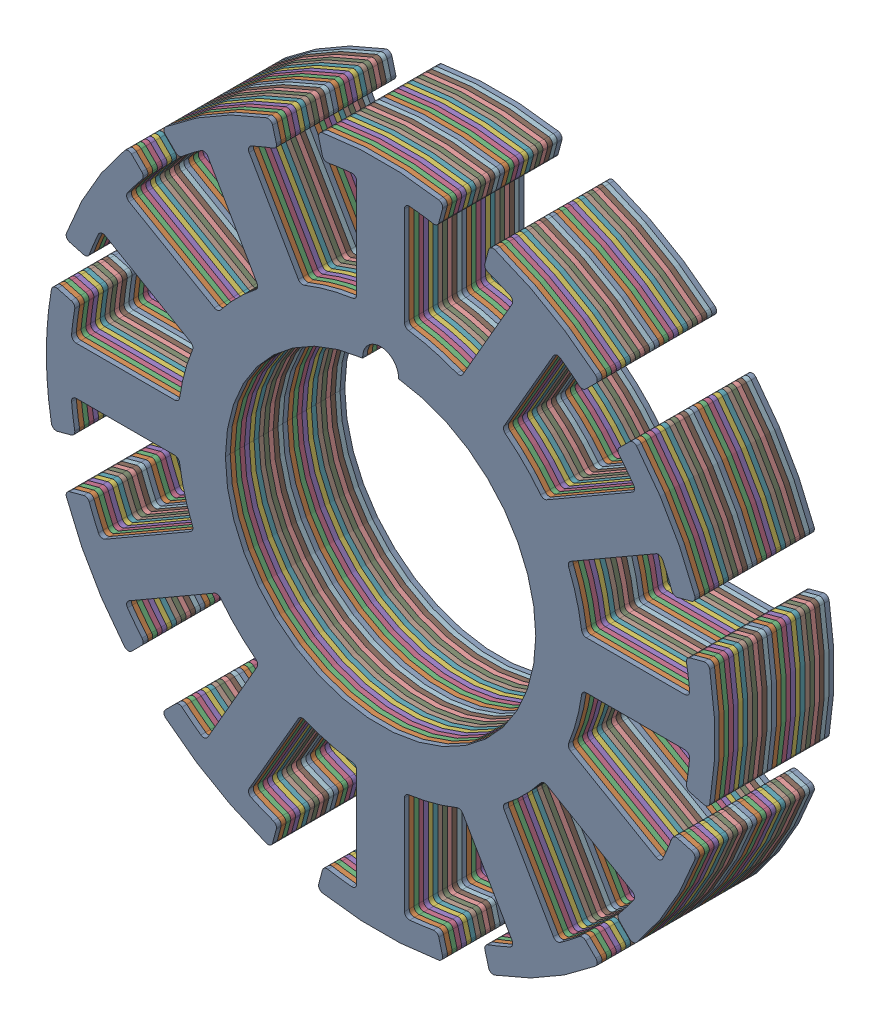
SolidWorks assembly 28x13x5mm-Stator.STEP, configuration Default. Lengths in mm.
Overall size (28 28 5).
30 component instances, 1 part files, 0 mates.
Components (placement in the parent):
- 28x13x1mm-Stator.STEP-1: 28x13x1mm-Stator.STEP [Default] at (34.0086 1.4103 18.4307) size (28 28 1)
  - 28x13-Stator Plate.STEP-1: 28x13-Stator Plate.STEP [Default] at (-28.2175 12.5042 6.2948) size (28 28 0.2)
  - 28x13-Stator Plate.STEP-2: 28x13-Stator Plate.STEP [Default] at (-28.2175 12.5042 6.0948) size (28 28 0.2)
  - 28x13-Stator Plate.STEP-3: 28x13-Stator Plate.STEP [Default] at (-28.2175 12.5042 5.8948) size (28 28 0.2)
  - 28x13-Stator Plate.STEP-4: 28x13-Stator Plate.STEP [Default] at (-28.2175 12.5042 5.6948) size (28 28 0.2)
  - 28x13-Stator Plate.STEP-5: 28x13-Stator Plate.STEP [Default] at (-28.2175 12.5042 5.4948) size (28 28 0.2)
- 28x13x1mm-Stator.STEP-2: 28x13x1mm-Stator.STEP [Default] at (34.0086 1.4103 17.4307) size (28 28 1)
  - 28x13-Stator Plate.STEP-1: 28x13-Stator Plate.STEP [Default] at (-28.2175 12.5042 6.2948) size (28 28 0.2)
  - 28x13-Stator Plate.STEP-2: 28x13-Stator Plate.STEP [Default] at (-28.2175 12.5042 6.0948) size (28 28 0.2)
  - 28x13-Stator Plate.STEP-3: 28x13-Stator Plate.STEP [Default] at (-28.2175 12.5042 5.8948) size (28 28 0.2)
  - 28x13-Stator Plate.STEP-4: 28x13-Stator Plate.STEP [Default] at (-28.2175 12.5042 5.6948) size (28 28 0.2)
  - 28x13-Stator Plate.STEP-5: 28x13-Stator Plate.STEP [Default] at (-28.2175 12.5042 5.4948) size (28 28 0.2)
- 28x13x1mm-Stator.STEP-3: 28x13x1mm-Stator.STEP [Default] at (34.0086 1.4103 16.4307) size (28 28 1)
  - 28x13-Stator Plate.STEP-1: 28x13-Stator Plate.STEP [Default] at (-28.2175 12.5042 6.2948) size (28 28 0.2)
  - 28x13-Stator Plate.STEP-2: 28x13-Stator Plate.STEP [Default] at (-28.2175 12.5042 6.0948) size (28 28 0.2)
  - 28x13-Stator Plate.STEP-3: 28x13-Stator Plate.STEP [Default] at (-28.2175 12.5042 5.8948) size (28 28 0.2)
  - 28x13-Stator Plate.STEP-4: 28x13-Stator Plate.STEP [Default] at (-28.2175 12.5042 5.6948) size (28 28 0.2)
  - 28x13-Stator Plate.STEP-5: 28x13-Stator Plate.STEP [Default] at (-28.2175 12.5042 5.4948) size (28 28 0.2)
- 28x13x1mm-Stator.STEP-4: 28x13x1mm-Stator.STEP [Default] at (34.0086 1.4103 15.4307) size (28 28 1)
  - 28x13-Stator Plate.STEP-1: 28x13-Stator Plate.STEP [Default] at (-28.2175 12.5042 6.2948) size (28 28 0.2)
  - 28x13-Stator Plate.STEP-2: 28x13-Stator Plate.STEP [Default] at (-28.2175 12.5042 6.0948) size (28 28 0.2)
  - 28x13-Stator Plate.STEP-3: 28x13-Stator Plate.STEP [Default] at (-28.2175 12.5042 5.8948) size (28 28 0.2)
  - 28x13-Stator Plate.STEP-4: 28x13-Stator Plate.STEP [Default] at (-28.2175 12.5042 5.6948) size (28 28 0.2)
  - 28x13-Stator Plate.STEP-5: 28x13-Stator Plate.STEP [Default] at (-28.2175 12.5042 5.4948) size (28 28 0.2)
- 28x13x1mm-Stator.STEP-5: 28x13x1mm-Stator.STEP [Default] at (34.0086 1.4103 14.4307) size (28 28 1)
  - 28x13-Stator Plate.STEP-1: 28x13-Stator Plate.STEP [Default] at (-28.2175 12.5042 6.2948) size (28 28 0.2)
  - 28x13-Stator Plate.STEP-2: 28x13-Stator Plate.STEP [Default] at (-28.2175 12.5042 6.0948) size (28 28 0.2)
  - 28x13-Stator Plate.STEP-3: 28x13-Stator Plate.STEP [Default] at (-28.2175 12.5042 5.8948) size (28 28 0.2)
  - 28x13-Stator Plate.STEP-4: 28x13-Stator Plate.STEP [Default] at (-28.2175 12.5042 5.6948) size (28 28 0.2)
  - 28x13-Stator Plate.STEP-5: 28x13-Stator Plate.STEP [Default] at (-28.2175 12.5042 5.4948) size (28 28 0.2)
